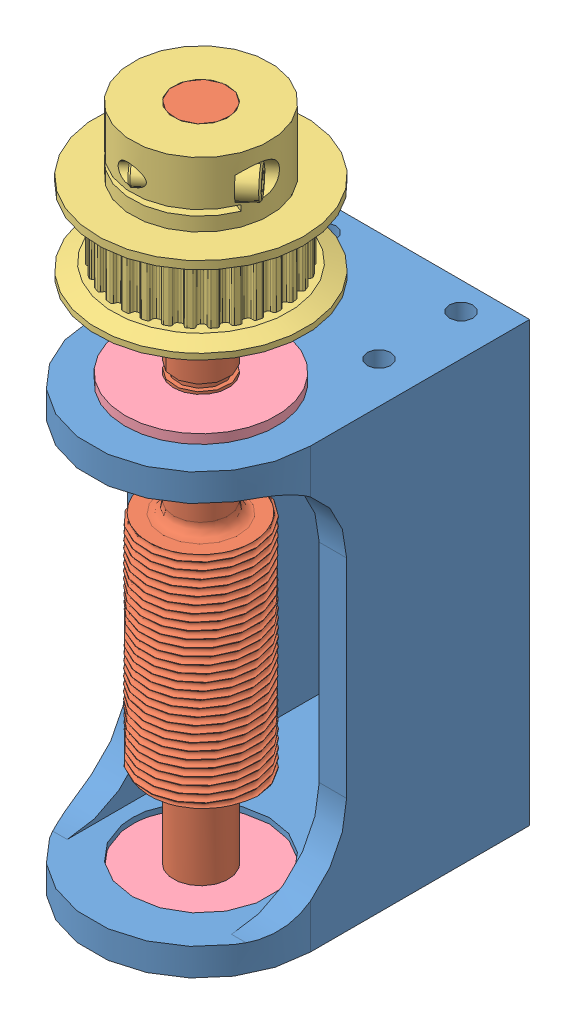
SolidWorks assembly spiral-drive-box, configuration Default. Lengths in mm.
Overall size (33.79 82.55 42.29).
5 component instances, 4 part files, 7 mates.
Components (placement in the parent):
- y05-spiral-drive-box-1: y05-spiral-drive-box [Default] at origin size (25.4 50.8 38.1)
- y04-spiral-drive-pulley-1: y04-spiral-drive-pulley [Default] at (0 -13.0586 25.4) x (-0.34248 0 0.939525) z (0 1 0) size (14.66 13.16 82.55)
- a_6d16-030df2508-sdp-si-p25bore-1: a_6d16-030df2508-sdp-si-p25bore [Default] at (0 44.8851 25.4) x (0.635929 0 0.771747) z (0 1 0) size (24 24 17.46)
- 000_rb-p25xp625-57155K324mcm-2: 000_rb-p25xp625-57155K324mcm [Default] at (0 22.86 25.4) x (0 -1 0) z (0.737312 0 0.675552) size (3.61 17.53 17.53)
- 000_rb-p25xp625-57155K324mcm-3: 000_rb-p25xp625-57155K324mcm [Default] at (0 -22.86 25.4) x (0 1 0) z (0 0 1) size (3.61 17.53 17.53)
Mates (geometry in assembly coordinates):
- Concentric1: concentric anti-aligned: cylinder of y05-spiral-drive-box-1; cylinder of y04-spiral-drive-pulley-1
- Coincident1: coincident aligned: plane of y04-spiral-drive-pulley-1 through (0 53.6164 25.4) normal (0 1 0); plane of a_6d16-030df2508-sdp-si-p25bore-1 through (6.1257 53.6164 20.3523) normal (0 1 0)
- Concentric2: concentric anti-aligned: cylinder of y04-spiral-drive-pulley-1; cylinder of a_6d16-030df2508-sdp-si-p25bore-1
- Coincident2: coincident anti-aligned: plane of y05-spiral-drive-box-1 through (-12.7 25.4 38.1) normal (0 1 0); plane of 000_rb-p25xp625-57155K324mcm-2 through (-6.4611 25.4 19.4801) normal (0 -1 0)
- Concentric3: concentric aligned: cylinder of y04-spiral-drive-pulley-1; cylinder of 000_rb-p25xp625-57155K324mcm-2
- Coincident3: coincident anti-aligned: plane of y05-spiral-drive-box-1 through (-12.7 -25.4 38.1) normal (0 -1 0); plane of 000_rb-p25xp625-57155K324mcm-3 through (0 -25.4 16.637) normal (0 1 0)
- Concentric4: concentric anti-aligned: cylinder of y04-spiral-drive-pulley-1; cylinder of 000_rb-p25xp625-57155K324mcm-3
